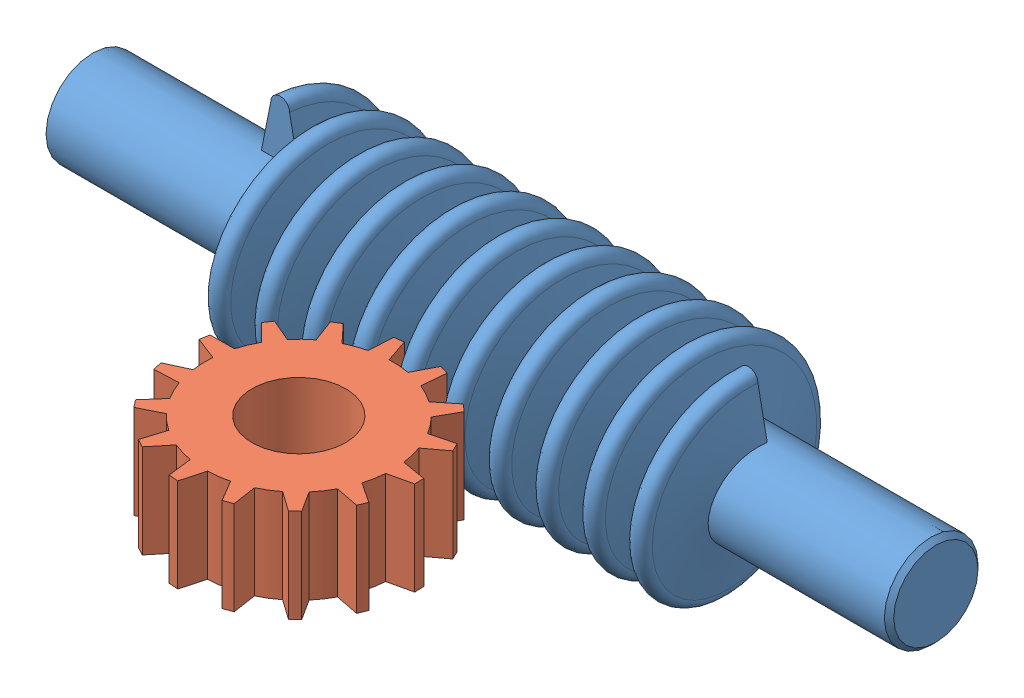
SolidWorks assembly Assem1, configuration Default. Lengths in mm.
Overall size (90 24 45.5).
2 component instances, 2 part files, 0 mates.
Components (placement in the parent):
- demowormgear-1: demowormgear [Default] at (-6.6677 62.6104 86.527) x (0 1 0) z (0 0 -1) size (24 90 24)
- gearforworm-1: gearforworm [Default] at (36.3329 56.0768 107.5389) x (-1 0 0) z (0 1 0) size (24.88 24.94 10)
